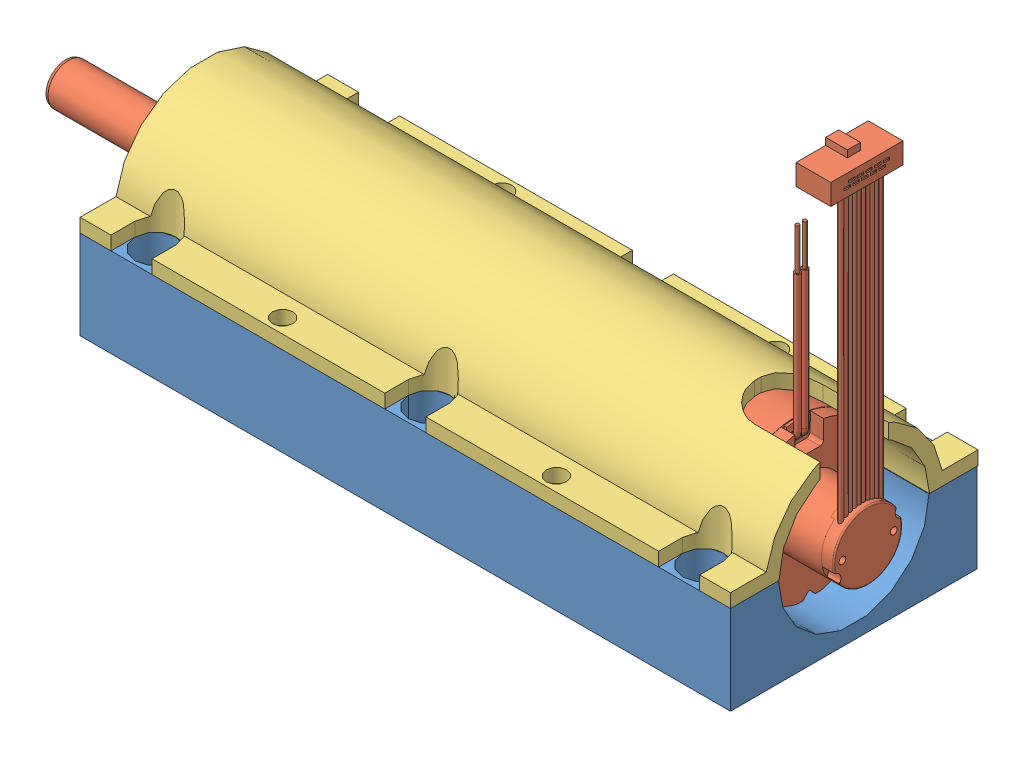
SolidWorks assembly Двигатель + Крепление, configuration По умолчанию. Lengths in mm.
Overall size (132.22 62.52 36.16).
3 component instances, 3 part files, 6 mates.
Components (placement in the parent):
- Крепление низ-1: Крепление низ [По умолчанию] at (-39.156 -1.5458 18) size (95 13 36)
- Привод-1: Привод [По умолчанию] at (-39.256 11.4542 0) x (1 0 0) z (0 -1 0) size (132.22 22 60.52)
- Крепление верх-1: Крепление верх [По умолчанию] at (-39.156 11.4542 -0.0795) size (95 13 36.16)
Mates (geometry in assembly coordinates):
- Концентричный1: concentric: cylinder of Крепление низ-1 through (-39.156 11.4542 0) axis (1 0 0) radius 11; cylinder of Привод-1 through (25.734 11.4542 0) axis (1 0 0) radius 11
- Совпадение1: coincident: circle of Крепление низ-1; circle of Привод-1
- Совпадение2: coincident anti-aligned: plane of Крепление низ-1 through (-39.156 11.4542 18) normal (0 1 0); plane of Крепление верх-1 through (55.844 11.4542 10.9205) normal (0 -1 0)
- Совпадение3: coincident anti-aligned: line of Крепление низ-1 through (-39.156 11.4542 18) axis (1 0 0); line of Крепление верх-1 through (5.344 11.4542 18) axis (-1 0 0)
- Совпадение4: coincident anti-aligned: line of Крепление низ-1 through (-39.156 11.4542 11) axis (0 0 1); line of Крепление верх-1 through (-39.156 11.4542 18) axis (0 0 -1)
- Параллельность1: parallel: plane of Крепление низ-1 through (-39.156 11.4542 -18) normal (0 0 -1); plane of Привод-1 through (47.334 24.4542 -2.1) normal (0 0 1)
